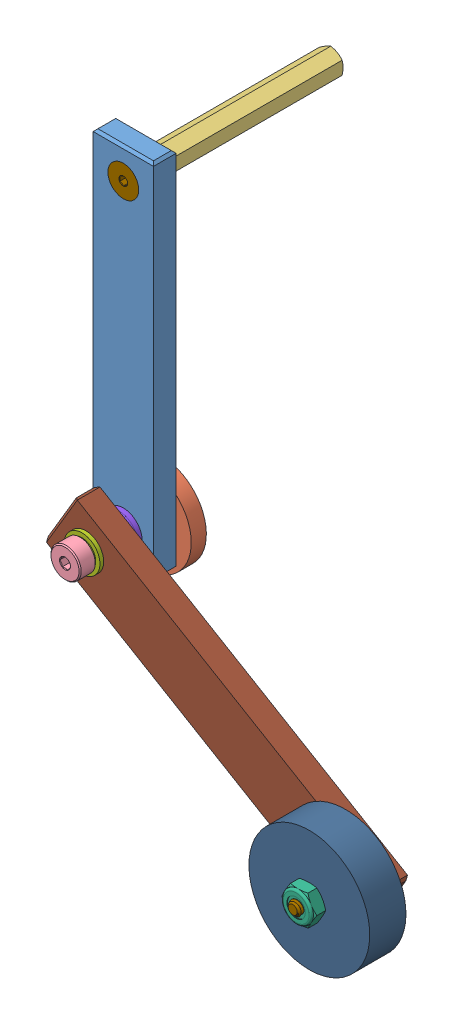
SolidWorks assembly pendulum, configuration Default. Lengths in mm.
Overall size (88.81 124.1 63.31).
19 component instances, 11 part files, 8 mates.
Components (placement in the parent):
- top_link_assy-1: top_link_assy [Default] at origin size (19.48 79.59 56.42) (flexible)
  - top_link-1: top_link [Default] at (0 -6.35 4.7625) x (0 1 0) z (-1 0 0) size (76.2 4.76 12.7)
  - RC22-1: RC22 [Default] at (0 -69.85 -3.175) x (0.022662 -0.999743 0) z (-0.999743 -0.022662 0) size (19.05 3.17 19.05)
  - _ALUM FEM THRDED HEX STANDOFF_91780A036-1: _ALUM FEM THRDED HEX STANDOFF_91780A036 [91780A036] at (0 -6.35 -20.0152) x (0.5 0.866025 0) z (0 0 1) size (4.76 5.5 38.96)
  - 4_40-5-8_5-32-94035A136-1: 4_40-5-8_5-32-94035A136 [94035A136] at (0 -69.85 17.018) x (0.844941 -0.534859 0) z (0 0 1) size (6.35 6.35 23.39)
  - bearing_spacer_ 99040A316-1: bearing_spacer_ 99040A316 [Default] at (0 -69.85 7.0993) x (0.923728 0.383049 0) z (0 0 -1) size (4.76 4.76 0.41)
  - bearing_spacer_ 99040A316-2: bearing_spacer_ 99040A316 [Default] at (0 -69.85 13.843) x (0.923728 0.383049 0) z (0 0 -1) size (4.76 4.76 0.41)
  - 4_40_THIN_LOCKNUT_90633A005-1: 4_40_THIN_LOCKNUT_90633A005 [90633A005] at (0 -69.85 -3.175) x (0.830959 0.556334 0) z (-0.556334 0.830959 0) size (6.35 2.86 7.33)
  - FR144-ZZ-1: FR144-ZZ [Default] at (0 -69.85 10.6331) x (-0.92036 -0.391073 0) z (0 0 1) size (7.52 7.52 2.8)
  - 4_40-Washer_AL_93286A005-new-1: 4_40-Washer_AL_93286A005-new [93286A005] at (0 -69.85 5.7277) x (0 0 -1) z (1 0 0) size (0.97 7.92 7.92)
  - 4_40-Washer_AL_93286A005-new-2: 4_40-Washer_AL_93286A005-new [93286A005] at (0 -69.85 6.6929) x (0 0 -1) z (0.987351 0.158553 0) size (0.97 7.92 7.92)
  - FR144-ZZ-2: FR144-ZZ [Default] at (0 -69.85 9.9028) x (-0.83595 0.548806 0) z (0 0 -1) size (7.52 7.52 2.8)
  - 4_40-625-countersunk-stainless-92210a112-1: 4_40-625-countersunk-stainless-92210a112 [92210A112] at (0 -6.35 4.7625) size (6.48 6.48 16.22)
  - 4_40-Washer_AL_93286A005-new-3: 4_40-Washer_AL_93286A005-new [93286A005] at (0 -6.35 -0.9652) x (0 0 1) z (-1 0 0) size (0.97 7.92 7.92)
- bottom_link_assy-1: bottom_link_assy [Default] at (-5.4624 -66.6119 7.8867) x (0.509935 0.860213 0) z (0 0 1) size (31.92 85.81 16.22)
  - Mass_blank-1: Mass_blank [Default] at (0 -69.85 4.7625) x (0.9527 0.303914 0) z (0 0 1) size (25.4 25.4 7.62)
  - 4_40_THIN_LOCKNUT_90633A005-1: 4_40_THIN_LOCKNUT_90633A005 [90633A005] at (0 -69.85 12.3825) x (0.853828 0.520556 0) z (0.520556 -0.853828 0) size (6.35 2.86 7.33)
  - bottom_link-1: bottom_link [Default] at (0 -6.35 4.7625) x (0 1 0) z (-1 0 0) size (76.2 4.76 12.7)
  - 4_40-625-countersunk-stainless-92210a112-1: 4_40-625-countersunk-stainless-92210a112 [92210A112] at (0 -69.85 0) x (-0.923728 -0.383049 0) z (0 0 -1) size (6.48 6.48 16.22)
Mates (geometry in assembly coordinates):
- Coincident28: coincident anti-aligned: plane of ? through (6.35 -63.5 12.319) normal (0 0 1); plane of ? through (6.35 -63.5 12.319) normal (0 0 -1)
- Coincident33: coincident anti-aligned: plane of top_link_assy-1/top_link-1 through (0 -6.35 0) normal (0 0 -1); plane of assembly through (0 0 0) normal (0 0 1)
- Coincident34: coincident aligned: plane of top_link_assy-1/top_link-1 through (0 0 0) normal (0 1 0); plane of assembly through (0 0 0) normal (0 1 0)
- Symmetric2: symmetric aligned: plane of top_link_assy-1/top_link-1 through (-6.35 -6.35 0) normal (-1 0 0); plane of top_link_assy-1/top_link-1 through (6.35 -6.35 0) normal (1 0 0); plane of assembly through (0 0 0) normal (1 0 0)
- Concentric33: concentric aligned: cylinder of top_link_assy-1/FR144-ZZ-1 through (0 -69.85 12.6492) axis (0 0 -1) radius 1.5875; cylinder of bottom_link_assy-1/bottom_link-1 through (0 -69.85 12.6492) axis (0 0 -1) radius 3.1623
- Coincident43: coincident anti-aligned: plane of bottom_link_assy-1/bottom_link-1 through (0 -69.85 7.8867) normal (0 0 -1); plane of top_link_assy-1/FR144-ZZ-2 through (0 -69.85 7.8867) normal (0 0 1)
- Concentric34: concentric anti-aligned: cylinder of top_link_assy-1/FR144-ZZ-2 through (0 -69.85 7.8867) axis (0 0 1) radius 3.175; cylinder of bottom_link_assy-1/bottom_link-1 through (0 -69.85 12.6492) axis (0 0 -1) radius 3.1623
- Coincident44: coincident anti-aligned: plane of top_link_assy-1/FR144-ZZ-1 through (0 -69.85 12.6492) normal (0 0 -1); plane of bottom_link_assy-1/bottom_link-1 through (0 -69.85 12.6492) normal (0 0 1)
